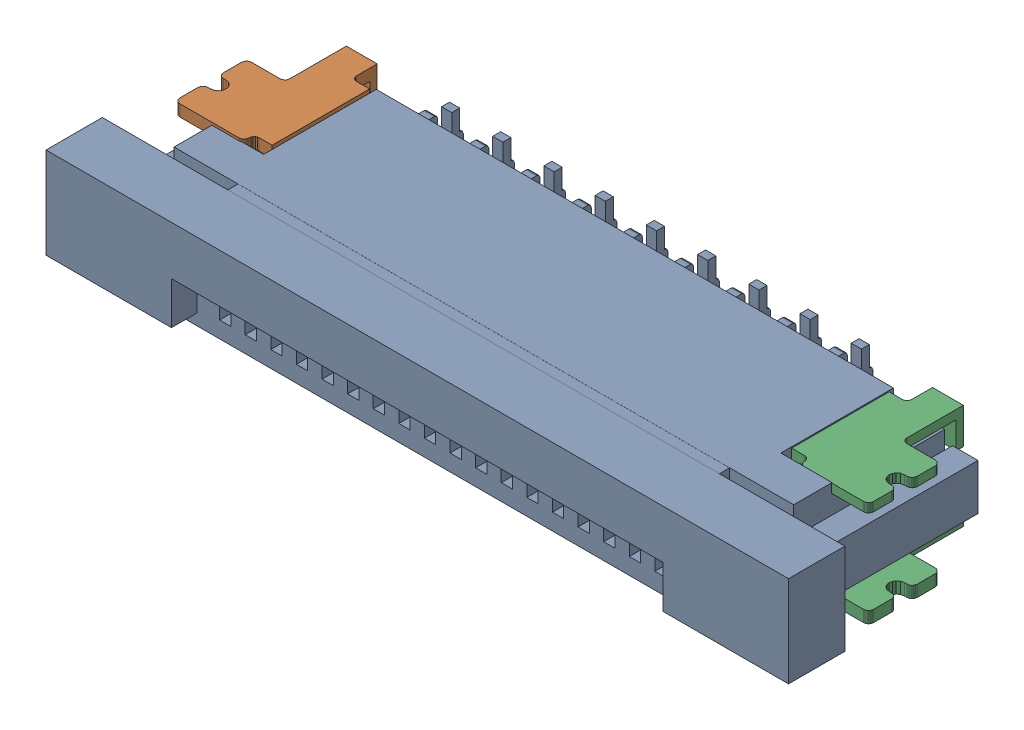
SolidWorks assembly P3主板_V1.0, configuration 默认. Lengths in mm.
Overall size (14.5 2.54 4.64).
4 component instances, 3 part files, 0 mates.
Components (placement in the parent):
- Header-FPC-ZIF-SMD-Vertical_Single-0.5-18-1: Header-FPC-ZIF-SMD-Vertical_Single-0.5-18 [默认] at (56.1085 5.2731 4.08) size (14.5 2.54 4.64)
  - ffc_fpc_affc20-18-050-shb-t_01-1: ffc_fpc_affc20-18-050-shb-t_01 [默认] at origin size (14.5 2.54 4.55)
  - ffc_fpc_affc20-18-050-shb-t_02-1: ffc_fpc_affc20-18-050-shb-t_02 [默认] at origin size (1.7 2.05 2.6)
  - ffc_fpc_affc20-18-050-shb-t_03-1: ffc_fpc_affc20-18-050-shb-t_03 [默认] at origin size (1.7 2.05 2.6)
